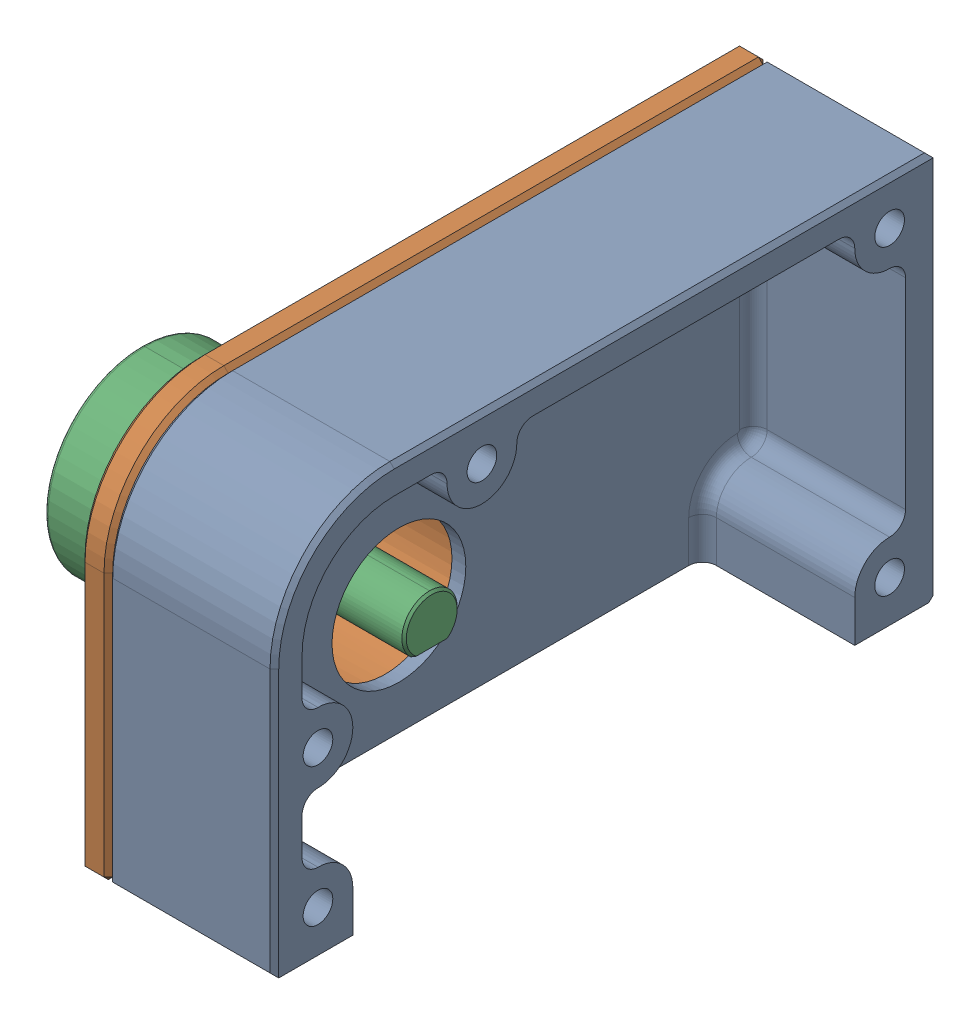
SolidWorks assembly MirrorPitch Sensor Assembly Left(Mirror), configuration Default. Lengths in mm.
Overall size (49.36 44.45 75.59).
3 component instances, 3 part files, 0 mates.
Components (placement in the parent):
- MirrorPitch Sensor Assembly Left(Mirror)-1: MirrorPitch Sensor Assembly Left(Mirror) [Default] at origin size (19.05 44.45 75.59)
- MirrorPitch Sensor Assembly Left(Mirror)_2-1: MirrorPitch Sensor Assembly Left(Mirror)_2 [Default] at origin size (16.83 44.45 75.59)
- 6127V1AxxxL.5FS-1: 6127V1AxxxL.5FS [6127V1A90L.5FS] at (57.3734 63 43.8404) x (0 1 0) z (0 0 1) size (22.23 35.66 22.23)
